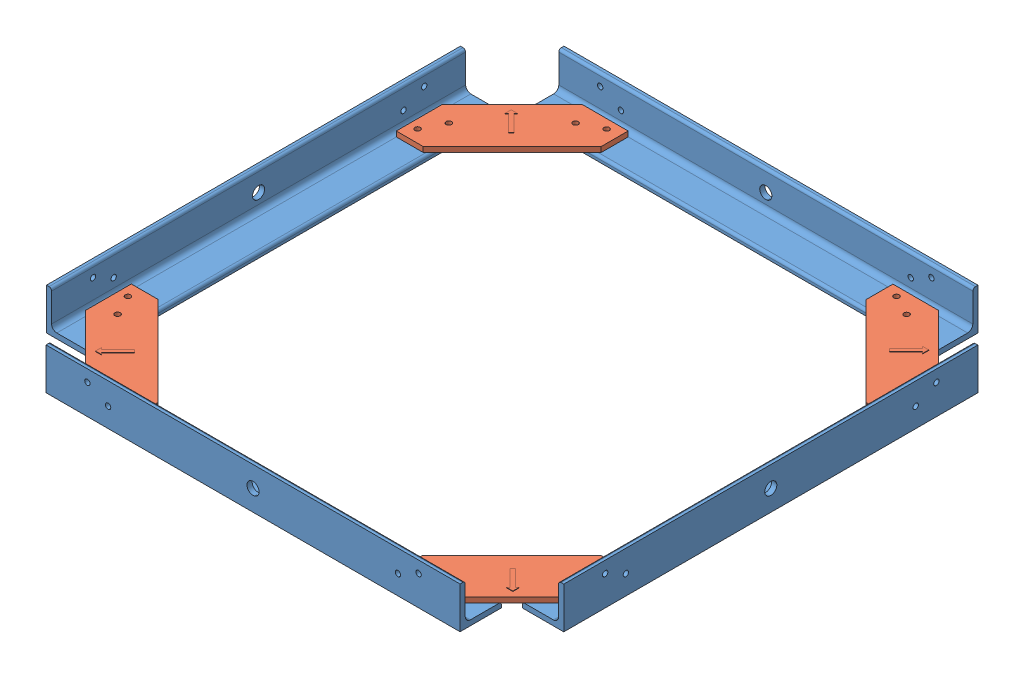
SolidWorks assembly test assemby 1, configuration Default. Lengths in mm.
Overall size (317.51 25.4 317.63).
8 component instances, 2 part files, 30 mates.
Components (placement in the parent):
- MOD Al L rod-4: MOD Al L rod [8982K401] at (158.011 130.5289 151.3983) size (25.4 25.4 254)
- MOD Al L rod-5: MOD Al L rod [8982K401] at (11.9531 130.5289 5.2213) x (0 0 -1) z (1 0 0) size (25.4 25.4 254)
- draft bracket-1: draft bracket [Default] at (164.361 121.0039 -1.0017) size (71.12 3.2 71.12)
- MOD Al L rod-7: MOD Al L rod [8982K401] at (11.834 130.5289 297.4562) x (0 0 1) z (-1 0 0) size (25.4 25.4 254)
- draft bracket-3: draft bracket [Default] at (164.234 121.0039 303.8062) x (0 0 1) z (-1 0 0) size (71.12 3.2 71.12)
- MOD Al L rod-9: MOD Al L rod [8982K401] at (-134.0969 130.5289 151.2713) x (-1 0 0) z (0 0 -1) size (25.4 25.4 254)
- draft bracket-6: draft bracket [Default] at (-140.4469 121.0039 -1.1287) x (0 0 -1) z (1 0 0) size (71.12 3.2 71.12)
- draft bracket-7: draft bracket [Default] at (-140.4469 121.0039 303.6713) x (-1 0 0) z (0 0 -1) size (71.12 3.2 71.12)
Mates (geometry in assembly coordinates):
- Coincident1: coincident aligned: circle of draft bracket-1; circle of MOD Alum 1x1x10 inches L rod-1
- Coincident3: coincident anti-aligned: circle of MOD Alum 1x1x10 inches L rod-2; circle of draft bracket-1
- Coincident23: coincident anti-aligned: circle of MOD Al L rod-4; circle of draft bracket-3
- Coincident24: coincident aligned: circle of MOD Al L rod-7; circle of draft bracket-3
- Coincident29: coincident anti-aligned: line of MOD Al L rod-7 through (-115.166 121.0039 303.8062) axis (1 0 0); line of draft bracket-3 through (121.054 121.0039 303.8062) axis (-1 0 0)
- Coincident35: coincident aligned: circle of MOD Al L rod-7; circle of draft bracket-3
- Coincident36: coincident aligned: line of MOD Al L rod-4 through (164.361 121.0039 278.3983) axis (0 0 -1); line of draft bracket-3 through (164.234 121.0039 260.6262) axis (0 0 -1)
- Parallel4: parallel anti-aligned: line of MOD Al L rod-7 through (-115.166 121.0039 303.8062) axis (1 0 0); line of draft bracket-3 through (121.054 121.0039 303.8062) axis (-1 0 0)
- Coincident38: coincident aligned: line of MOD Al L rod-7 through (-115.166 121.0039 303.8062) axis (1 0 0); line of draft bracket-7 through (-97.2635 121.0039 303.6715) axis (1 0 0)
- Coincident39: coincident anti-aligned: circle of MOD Al L rod-7; circle of draft bracket-7
- Coincident40: coincident anti-aligned: line of MOD Al L rod-5 through (138.9531 121.0039 -1.1287) axis (-1 0 0); line of draft bracket-6 through (-97.2669 121.0039 -1.1287) axis (1 0 0)
- Coincident41: coincident aligned: circle of MOD Al L rod-5; circle of draft bracket-6
- Coincident42: coincident aligned: circle of MOD Al L rod-9; circle of draft bracket-7
- Coincident43: coincident anti-aligned: circle of MOD Al L rod-9; circle of draft bracket-6
- Coincident44: coincident aligned: line of MOD Al L rod-9 through (-140.4473 121.0039 24.2716) axis (0.000018 0 1); line of draft bracket-6 through (-140.4469 121.0039 42.0513) axis (0 0 1)
- Coincident45: coincident aligned: circle of MOD Al L rod-5; circle of draft bracket-6
- Coincident46: coincident aligned: circle of MOD Al L rod-5; circle of draft bracket-6
- Coincident47: coincident anti-aligned: circle of MOD Al L rod-9; circle of draft bracket-6
- Coincident51: coincident: circle of MOD Al L rod-9; circle of draft bracket-6
- Coincident52: coincident anti-aligned: circle of MOD Al L rod-5; circle of draft bracket-1
- Coincident55: coincident aligned: circle of MOD Al L rod-4; circle of draft bracket-1
- Coincident56: coincident aligned: circle of MOD Al L rod-4; circle of draft bracket-1
- Parallel5: parallel aligned: line of MOD Al L rod-5 through (138.9531 121.0039 -1.1287) axis (-1 0 0); line of draft bracket-1 through (113.561 121.0039 -1.0017) axis (-1 0 0)
- Coincident59: coincident anti-aligned: circle of MOD Al L rod-4; circle of draft bracket-3
- Coincident61: coincident aligned: circle of MOD Al L rod-7; circle of draft bracket-3
- Coincident62: coincident aligned: circle of MOD Al L rod-7; circle of draft bracket-3
- Parallel6: parallel aligned: line of MOD Al L rod-4 through (164.361 121.0039 278.3983) axis (0 0 -1); line of draft bracket-3 through (164.234 121.0039 253.0062) axis (0 0 -1)
- Coincident64: coincident aligned: circle of MOD Al L rod-9; circle of draft bracket-7
- Parallel8: parallel aligned: line of MOD Al L rod-7 through (-115.166 121.0039 303.8062) axis (1 0 0); line of draft bracket-7 through (-89.6469 121.0039 303.6713) axis (1 0 0)
- Coincident73: coincident anti-aligned: line of MOD Al L rod-9 through (-140.4469 121.0039 24.2713) axis (0 0 1); line of draft bracket-7 through (-140.4469 121.0039 252.8713) axis (0 0 -1)
